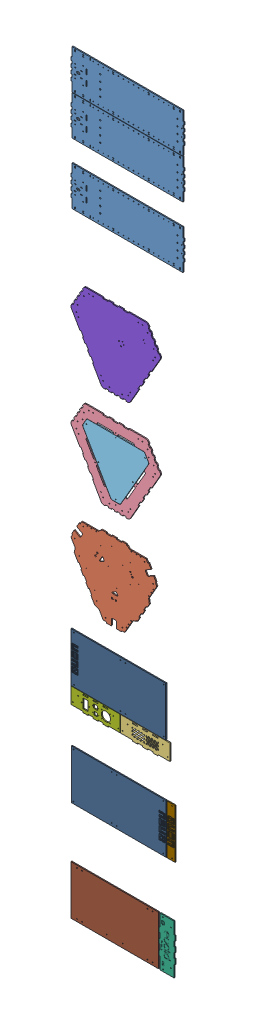
SolidWorks assembly acrylic-lasercut-layout-600x400, configuration Default. Lengths in mm.
Overall size (674.7 3900 216.11).
14 component instances, 11 part files, 38 mates.
Components (placement in the parent):
- acrylic-wall-1: acrylic-wall [Default] at (-200 -402.6955 220) x (0 0 -1) z (0 -1 0) size (5 560 195.39)
- acrylic-wall-2: acrylic-wall [Default] at (-200 -100.0864 220) x (0 0 -1) z (0 -1 0) size (5 560 195.39)
- acrylic-wall-3: acrylic-wall [Default] at (-200 97.3045 220) x (0 0 -1) z (0 -1 0) size (5 560 195.39)
- acrylic-base-1: acrylic-base [Default] at (-82.2714 -1973.4567 -15) x (0.866025 0.5 0) z (-0.5 0.866025 0) size (388.46 5 425.46)
- acrylic-bay-cover-1: acrylic-bay-cover [Default] at (72.6537 -2540.7691 168.4567) x (0.866025 0 -0.5) z (0.5 0 0.866025) size (213.61 85 126.21)
- acrylic-bottom-1: acrylic-bottom [Default] at (-73.3543 -1473.4567 -90) x (-0.866025 0.5 0) z (-0.5 -0.866025 0) size (388.46 5 443.29)
- acrylic-electronics-cover-1: acrylic-electronics-cover [Default] at (-73.3543 -1473.4567 -90) x (-0.866025 0.5 0) z (-0.5 -0.866025 0) size (285.46 5 326.68)
- acrylic-pscover-1: acrylic-pscover [Default] at (235.75 -3426.8846 168.4567) x (0 -0.866025 -0.5) z (0 -0.5 0.866025) size (213.61 80 126.21)
- acrylic-switch-cover-1: acrylic-switch-cover [Default] at (-173.1154 -2540.7691 168.4567) x (0.866025 0 -0.5) z (0.5 0 0.866025) size (213.61 85 126.21)
- acrylic-top-1: acrylic-top [Default] at (-73.3543 -973.4567 -460) x (0.866025 0.5 0) z (0.5 -0.866025 0) size (388.46 5 443.29)
- acrylic-nameplate-1: acrylic-nameplate [Default] at (-238.9978 -2928.4107 168.4567) x (0 -0.866025 -0.5) z (0 -0.5 0.866025) size (213.61 40 126.21)
- acrylic-window-bl-1: acrylic-window-bl [Default] at (-282.9183 -2928.9567 -163.4567) x (0 0.866025 0.5) z (0 0.5 -0.866025) size (213.61 469.5 126.21)
- acrylic-window-bl-2: acrylic-window-bl [Default] at (164.75 -2426.8846 168.4567) x (0 0.866025 -0.5) z (0 0.5 0.866025) size (213.61 469.5 126.21)
- acrylic-door-1: acrylic-door [Default] at (124.25 -3426.3846 168.4567) x (0 0.866025 -0.5) z (0 0.5 0.866025) size (212.74 433.75 125.71)
Mates (geometry in assembly coordinates):
- Coincident1: coincident anti-aligned: plane of acrylic-wall-3 through (-290 154.9896 0) normal (0 0 -1); plane of assembly through (0 0 0) normal (0 0 1)
- Coincident2: coincident anti-aligned: plane of acrylic-wall-2 through (-290 -42.4014 0) normal (0 0 -1); plane of assembly through (0 0 0) normal (0 0 1)
- Coincident3: coincident anti-aligned: plane of acrylic-wall-1 through (-290 -345.0104 0) normal (0 0 -1); plane of assembly through (0 0 0) normal (0 0 1)
- Coincident4: coincident: plane of acrylic-base-1 through (-82.2714 -1973.4567 0) normal (0 0 -1); plane of assembly through (0 0 0) normal (0 0 1)
- Coincident5: coincident anti-aligned: plane of acrylic-bay-cover-1 through (72.6537 -2590.6242 0) normal (0 0 -1); plane of assembly through (0 0 0) normal (0 0 1)
- Coincident6: coincident anti-aligned: plane of acrylic-pscover-1 through (235.75 -3426.8846 0) normal (0 0 -1); plane of assembly through (0 0 0) normal (0 0 1)
- Coincident7: coincident anti-aligned: plane of acrylic-switch-cover-1 through (-173.1154 -2540.7691 0) normal (0 0 -1); plane of assembly through (0 0 0) normal (0 0 1)
- Coincident8: coincident anti-aligned: plane of acrylic-bottom-1 through (-73.3543 -1473.4567 0) normal (0 0 -1); plane of assembly through (0 0 0) normal (0 0 1)
- Coincident9: coincident anti-aligned: plane of acrylic-electronics-cover-1 through (-73.3543 -1473.4567 0) normal (0 0 -1); plane of assembly through (0 0 0) normal (0 0 1)
- Coincident10: coincident anti-aligned: plane of acrylic-top-1 through (-131.0394 -1176.4567 0) normal (0 0 -1); plane of assembly through (0 0 0) normal (0 0 1)
- Coincident11: coincident anti-aligned: plane of acrylic-nameplate-1 through (-238.9978 -2928.4107 0) normal (0 0 -1); plane of assembly through (0 0 0) normal (0 0 1)
- Coincident13: coincident anti-aligned: plane of acrylic-door-1 through (124.25 -3426.3846 0) normal (0 0 -1); plane of assembly through (0 0 0) normal (0 0 1)
- Coincident14: coincident anti-aligned: plane of acrylic-window-bl-2 through (164.75 -2426.8846 0) normal (0 0 -1); plane of assembly through (0 0 0) normal (0 0 1)
- Coincident20: coincident aligned: plane of acrylic-wall-2 through (265 -48.8439 5) normal (1 0 0); plane of acrylic-wall-3 through (265 46.062 5) normal (1 0 0)
- Distance1: distance = 5 mm: line of assembly; plane of acrylic-wall-3 through (-290 195 5) normal (0 1 0)
- Distance2: distance = 5 mm: plane of acrylic-wall-3 through (-295 148.5471 5) normal (-1 0 0); line of assembly
- Distance3: distance = 2 mm anti-aligned: plane of acrylic-wall-3 through (-290 -0.3909 5) normal (0 -1 0); plane of acrylic-wall-2 through (-290 -2.3909 5) normal (0 1 0)
- Distance4: distance = 5 mm: plane of acrylic-wall-1 through (-290 -305 5) normal (0 1 0); line of assembly
- Distance5: distance = 5 mm: plane of acrylic-wall-1 through (-295 -351.4529 5) normal (-1 0 0); line of assembly
- Distance6: distance = 5 mm: plane of acrylic-top-1 through (-110.8543 -805 5) normal (0 1 0); line of assembly
- Distance7: distance = 5 mm: cylinder of acrylic-top-1 through (-278 -921.9134 5) axis (0 0 -1) radius 17; line of assembly
- Coincident30: coincident anti-aligned: plane of acrylic-window-bl-1 through (-282.9183 -2928.9567 0) normal (0 0 -1); plane of assembly through (0 0 0) normal (0 0 1)
- Distance10: distance = 5 mm: plane of acrylic-door-1 through (-295 -3305 110.3386) normal (0 1 0); line of assembly
- Distance11: distance = 5 mm: line of assembly; plane of acrylic-door-1 through (-295 -3304.75 455.482) normal (-1 0 0)
- Distance12: distance = 2 mm anti-aligned: plane of acrylic-pscover-1 through (140.75 -3364.4846 5) normal (-1 0 0); plane of acrylic-door-1 through (138.75 -3426.3846 455.482) normal (1 0 0)
- Coincident34: coincident aligned: plane of acrylic-pscover-1 through (146 -3305 5) normal (0 1 0); plane of acrylic-door-1 through (-295 -3305 110.3386) normal (0 1 0)
- Distance13: distance = 5 mm: plane of ? through (-230.1299 -1305 0) normal (0 1 0)
- Distance14: distance = 5 mm: cylinder of ? through (-278 -1421.9134 0) axis (0 0 1) radius 17
- Distance15: distance = 0.5 mm anti-aligned: plane of acrylic-bottom-1 through (-219.1603 -1370 -555) normal (0.866025 -0.5 0); plane of acrylic-electronics-cover-1 through (-218.7272 -1370.25 -555) normal (-0.866025 0.5 0)
- Distance16: distance = 0.5 mm anti-aligned: plane of acrylic-bottom-1 through (72.4516 -1370 -555) normal (-0.866025 -0.5 0); plane of acrylic-electronics-cover-1 through (72.0186 -1370.25 -555) normal (0.866025 0.5 0)
- Distance17: distance = 5 mm: plane of acrylic-base-1 through (-119.7714 -1805 34.4365) normal (0 1 0); line of assembly
- Distance18: distance = 5 mm: line of acrylic-base-1 through (-295 -1911.9134 5) axis (0 0 -1); line of assembly
- Distance19: distance = 5 mm: plane of acrylic-window-bl-2 through (-295 -2305 5) normal (0 1 0); line of assembly
- Distance20: distance = 5 mm: plane of acrylic-window-bl-2 through (-295 -2305 5) normal (-1 0 0); line of assembly
- Coincident43: coincident aligned: plane of acrylic-switch-cover-1 through (-295 -2630.5191 5) normal (-1 0 0); plane of acrylic-window-bl-2 through (-295 -2305 5) normal (-1 0 0)
- Distance21: distance = 2 mm anti-aligned: plane of acrylic-switch-cover-1 through (-51.2309 -2550.7691 248.8204) normal (0 1 0); plane of acrylic-window-bl-2 through (-295 -2548.7691 5) normal (0 -1 0)
- Distance22: distance = 2 mm anti-aligned: plane of acrylic-bay-cover-1 through (-49.2309 -2630.5191 5) normal (-1 0 0); plane of acrylic-switch-cover-1 through (-51.2309 -2630.5191 5) normal (1 0 0)
- Distance23: distance = 2 mm anti-aligned: plane of acrylic-bay-cover-1 through (-49.2309 -2550.7691 -243.8204) normal (0 1 0); plane of acrylic-window-bl-2 through (-295 -2548.7691 5) normal (0 -1 0)
